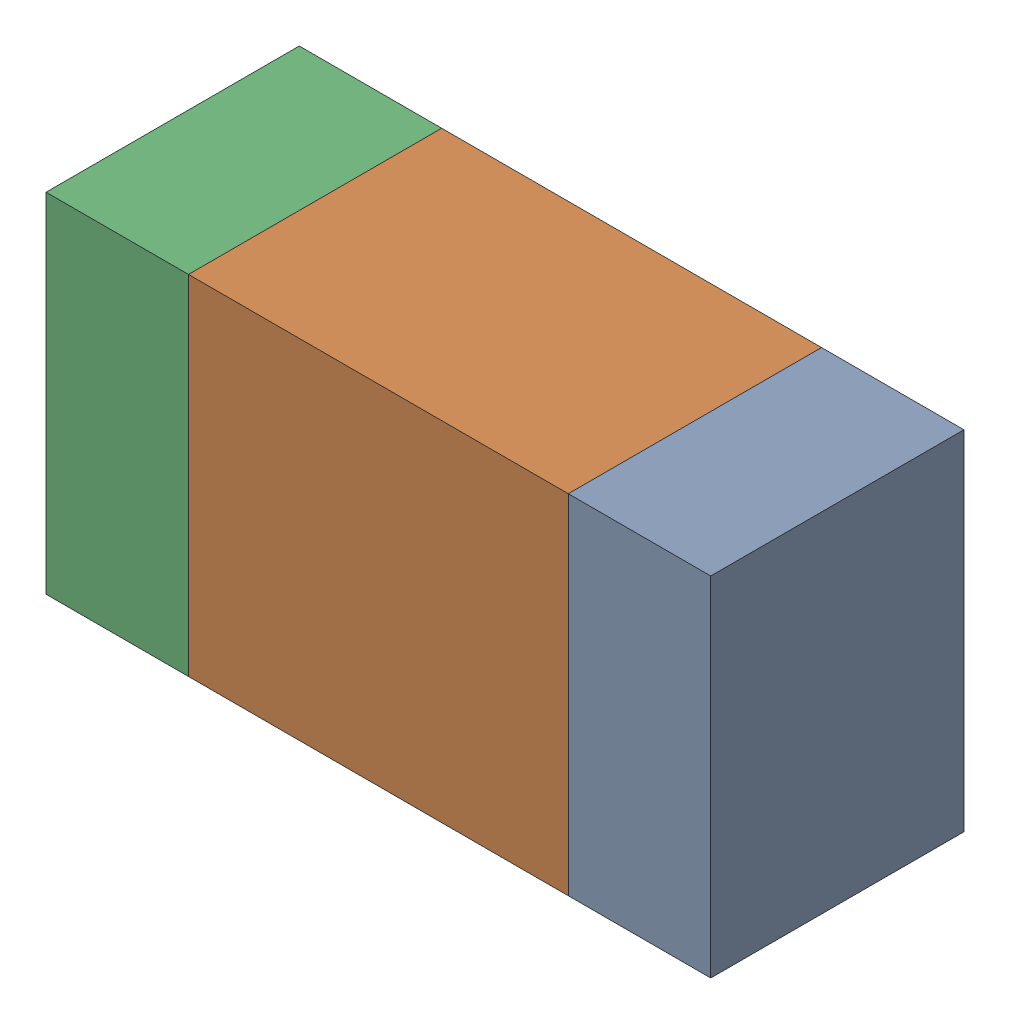
SolidWorks assembly R114_1PCB, configuration Default. Lengths in mm.
Overall size (1.05 0.55 0.4).
6 component instances, 2 part files, 0 mates.
Components (placement in the parent):
- 854785432-1: 854785432 [Default] at (112.8124 120.6999 0) size (0.22 0.55 0.4)
  - Extruded-1: Extruded [Default] at origin size (0.22 0.55 0.4)
- 854785568-1: 854785568 [Default] at (112.3999 120.6999 0) size (0.6 0.55 0.4)
  - Extruded_2-1: Extruded_2 [Default] at origin size (0.6 0.55 0.4)
- 854785432-2: 854785432 [Default] at (111.9874 120.6999 0) size (0.22 0.55 0.4)
  - Extruded-1: Extruded [Default] at origin size (0.22 0.55 0.4)
